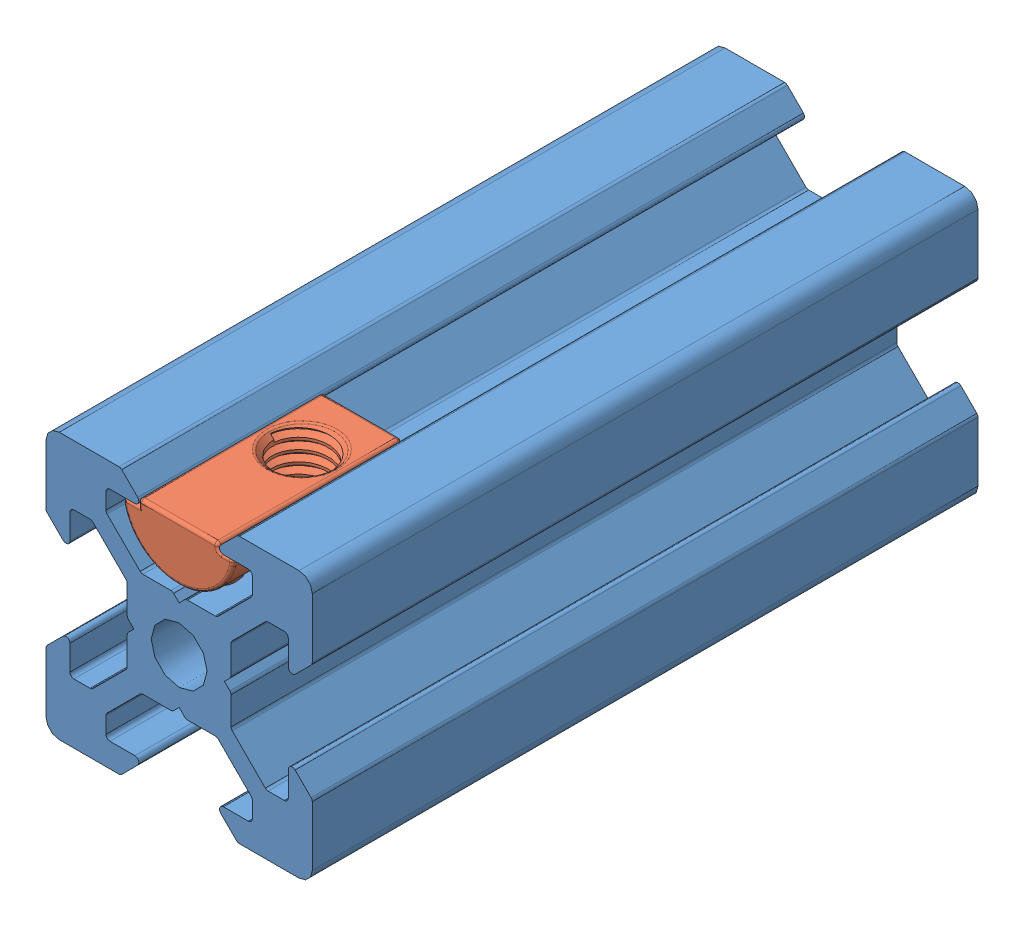
SolidWorks assembly T-V-SLOT-boll2, configuration По умолчанию. Lengths in mm.
Overall size (20 20 50).
2 component instances, 2 part files, 2 mates.
Components (placement in the parent):
- 20x20vSlot-1: 20x20vSlot [По умолчанию] at origin size (20 20 50)
- T-V-SLOT-boll-1: T-V-SLOT-boll [По умолчанию] at (-0.0786 4.5 43.1) x (-1 0 0) z (0 0 -1) size (8.2 5.46 13.8)
Mates (geometry in assembly coordinates):
- Совпадение1: coincident anti-aligned: plane of 2020V-1 through (-2.6 8.2 50) normal (0 -1 0); plane of Т-Сухарь паз 6-1 through (4.0214 8.2 50) normal (0 1 0)
- Совпадение3: coincident: plane of 2020V-1 through (0 0 50) normal (0 0 1); plane of Т-Сухарь паз 6 с шариком-1 through (-0.0786 8.7266 50) normal (0 0 1)
